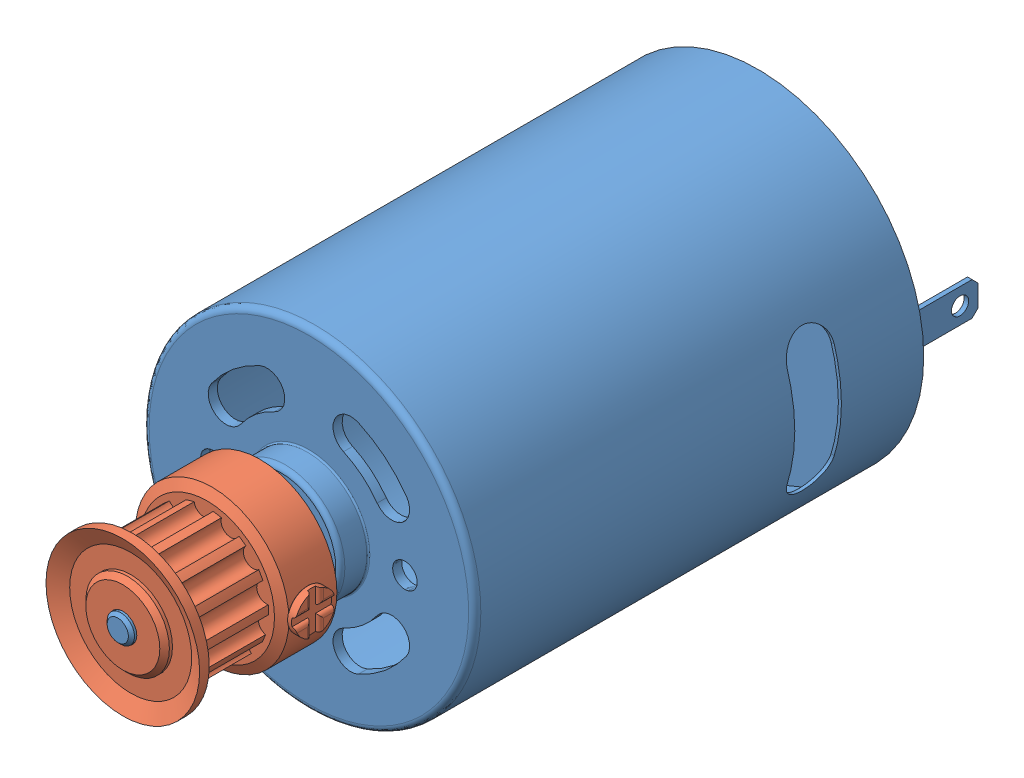
SolidWorks assembly DC_Motor_Pully, configuration Default. Lengths in mm.
Overall size (82.91 82.91 179.98).
2 component instances, 2 part files, 2 mates.
Components (placement in the parent):
- S400-1: S400 [Default] at (39.8441 18.2586 41.7559) size (82.91 82.91 179.98)
- pulley-2: pulley [Default] at (39.6891 16.9164 109.305) x (0 0 1) z (-1 0 0) size (35.52 38.4 40.25)
Mates (geometry in assembly coordinates):
- Concentric2: concentric: cylinder of S400-1 through (39.8441 18.2586 137.1445) axis (0 0 -1) radius 3.429; cylinder of pulley-2 through (39.8441 18.2586 100.3671) axis (0 0 1) radius 3.5
- Distance2: distance = 11 mm anti-aligned: plane of S400-1 through (39.8441 18.2586 89.3671) normal (0 0 1); plane of pulley-2 through (39.8441 35.0586 100.3671) normal (0 0 -1)
